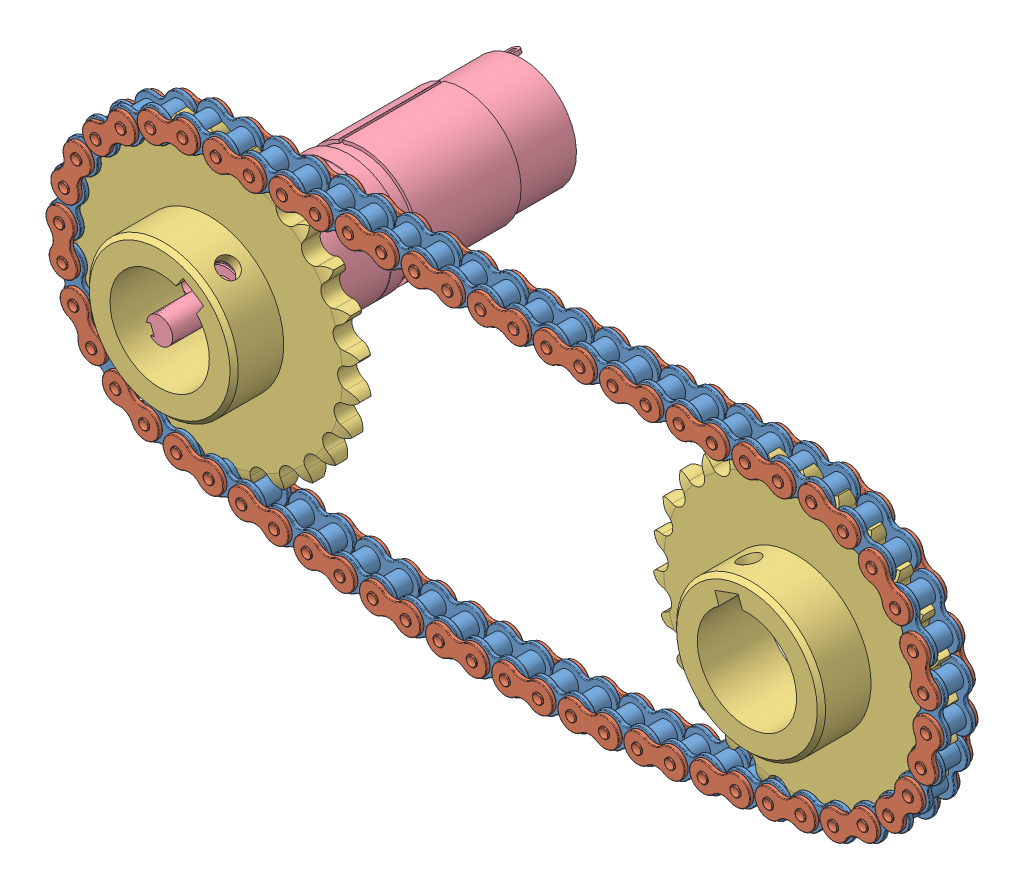
SolidWorks assembly chain drive and dc motor, configuration Default. Lengths in mm.
Overall size (376.19 156.56 146).
7 component instances, 4 part files, 5 mates.
Components (placement in the parent):
- Chain Drive-1: Chain Drive [Default] at (171.0759 206.2614 266.5858) size (376.77 156.56 30.44)
  - Chain A-1: Chain A [Default] at (-3.9373 5.8722 -1.9118) size (345.06 131.12 15.57)
    - Inner Chain-1: Inner Chain [Default] at (120.3815 217.874 272.3658) size (345.06 131.12 11.1)
    - Outer Chain-1: Outer Chain [Default] at (158.3912 217.874 270.6371) size (343.48 129.27 15.57)
  - Sprocket-1: Sprocket [Default] at (14.8599 170.457 272.397) x (0.831249 -0.555901 0) z (0 0 1) size (113.36 112.54 26.52)
  - Sprocket-2: Sprocket [Default] at (240.2692 170.457 272.397) x (0.94097 0.33849 0) z (0 0 1) size (113.36 112.54 26.52)
- DC Motor-1: DC Motor [Default] at (185.9358 376.7184 426.2464) x (0.931343 0.364143 0) z (0.364143 -0.931343 0) size (45 146.01 45)
Mates (geometry in assembly coordinates):
- Coincident1: coincident: plane of assembly; plane of assembly; plane of Chain Drive-1/Sprocket-1 through (201.8207 400.4713 565.2464) normal (0 0 1); plane of DC Motor-1 through (185.9358 376.7184 565.2464) normal (0 0 1)
- Parallel1: parallel: cylinder of assembly; cylinder of assembly; cylinder of Chain Drive-1/Sprocket-1 through (185.9358 376.7184 546.1964) axis (0 0 -1) radius 19.05; cylinder of DC Motor-1 through (185.9358 376.7184 537.7464) axis (0 0 -1) radius 22.5
- Concentric2: concentric: cylinder of assembly; cylinder of assembly; cylinder of Chain Drive-1/Sprocket-1 through (185.9358 376.7184 546.1964) axis (0 0 -1) radius 19.05; cylinder of DC Motor-1 through (185.9358 376.7184 537.7464) axis (0 0 -1) radius 22.5
- Coincident3: coincident: circle of assembly; plane of assembly; circle of Chain Drive-1/Sprocket-1; plane of DC Motor-1 through (185.9358 376.7184 537.7464) normal (0 0 1)
- Tangent4: tangent: plane of assembly; cylinder of assembly; plane of Chain Drive-1/Sprocket-1 through (201.8207 400.4713 565.2464) normal (0 0 1); cylinder of DC Motor-1 through (185.9358 376.7184 537.7464) axis (0 0 -1) radius 22.5
